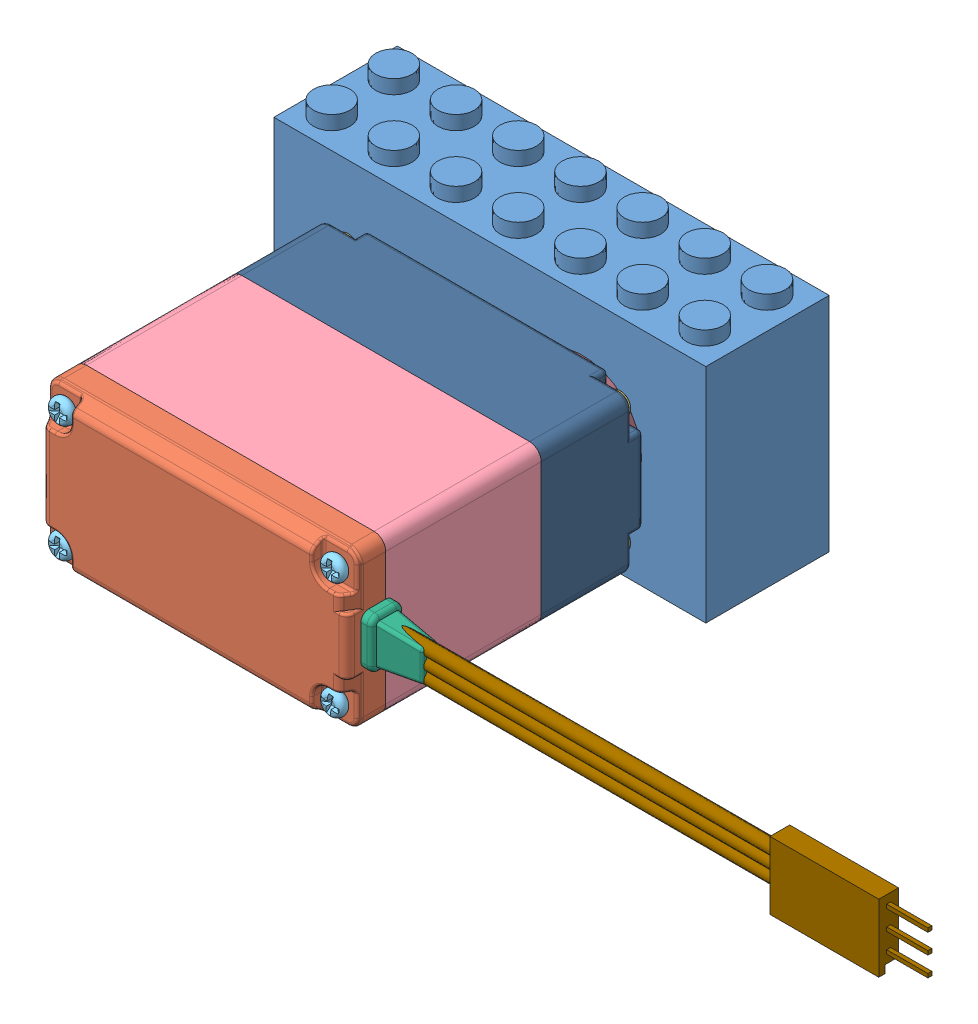
SolidWorks assembly Assembly of motor to mount, configuration Default. Lengths in mm.
Overall size (120.89 30.38 56.59).
22 component instances, 13 part files, 12 mates.
Components (placement in the parent):
- Vex Motor to LEGO mount-1: Vex Motor to LEGO mount [Default] at (39.2754 -37.007 4.4169) size (55.56 30.38 15.87)
- VEX-MOTOR-1: VEX-MOTOR [Default] at (-25.3861 -22.7195 0.5263) size (111.13 20 53.77)
  - Vex-Motor-Bottom-Plate-1: Vex-Motor-Bottom-Plate [Default] at (0 0 25) x (-1 0 0) z (0 0 -1) size (40.01 20 5)
  - Vex-Motor-Screw-Top-Simple-1: Vex-Motor-Screw-Top-Simple [Default] at (17.5 -7.5 -1.6) x (1 0 0) z (0 1 0) size (3.04 1.35 3.04)
  - Vex-Motor-Bottom-Housing-1: Vex-Motor-Bottom-Housing [Default] at origin size (40 20 27)
  - Vex-Motor-Screw-Bottom-Simple-1: Vex-Motor-Screw-Bottom-Simple [Default] at (-17.5 7.5 22.5) x (1 0 0) z (0 -1 0) size (3.04 1.35 3.04)
  - Vex-Wire-Support-1: Vex-Wire-Support [Default] at (18.6 0 21.1) x (0 1 0) z (-1 0 0) size (6.41 4.2 9.6)
  - Vex-Motor-Output-Gear-1: Vex-Motor-Output-Gear [Default] at (9.9 0 -3.25) x (0.000313 1 0) z (0 0 -1) size (17.29 17.28 12.55)
  - Insert-Nut-632-Simple-1: Insert-Nut-632-Simple [Default] at (-2.8 0 -19.4731) x (0.660354 0.750955 0) z (-0.750955 0.660354 0) size (5.5 9.3 5.5)
  - Vex-Motor-Screw-Top-Simple-2: Vex-Motor-Screw-Top-Simple [Default] at (17.5 7.5 -1.6) x (1 0 0) z (0 1 0) size (3.04 1.35 3.04)
  - Vex-Motor-PWM-1: Vex-Motor-PWM [Default] at (78.8 0 21.1) x (-1 0 0) z (0 0 1) size (69.31 8.7 2.54)
  - Vex-Motor-Screw-Bottom-Simple-2: Vex-Motor-Screw-Bottom-Simple [Default] at (17.5 7.5 22.5) x (-1 0 0) z (0 1 0) size (3.04 1.35 3.04)
  - Vex-Motor-Screw-Bottom-Simple-3: Vex-Motor-Screw-Bottom-Simple [Default] at (17.5 -7.5 22.5) x (0.990547 -0.137172 0) z (-0.137172 -0.990547 0) size (3.04 1.35 3.04)
  - Vex-Motor-Screw-Top-Simple-3: Vex-Motor-Screw-Top-Simple [Default] at (-17.5 7.5 -1.6) x (1 0 0) z (0 1 0) size (3.04 1.35 3.04)
  - Vex-Motor-Screw-Bottom-Simple-4: Vex-Motor-Screw-Bottom-Simple [Default] at (-17.5 -7.5 22.5) x (1 0 0) z (0 -1 0) size (3.04 1.35 3.04)
  - Vex-Motor-Top-Housing-1: Vex-Motor-Top-Housing [Default] x (1 0 0) z (0 0 -1) size (40.03 20 28.1)
  - Insert-Nut-632-Simple-2: Insert-Nut-632-Simple [Default] at (-15.5 0 -19.4731) x (-0.689985 0.723823 0) z (-0.723823 -0.689985 0) size (5.5 9.3 5.5)
  - Vex-Motor-Screw-Top-Simple-4: Vex-Motor-Screw-Top-Simple [Default] at (-17.5 -7.5 -1.6) x (1 0 0) z (0 1 0) size (3.04 1.35 3.04)
- SCREW-632-0250-1: SCREW-632-0250 [Default] at (-28.1861 -22.7195 -30.6979) x (0 0 1) z (-0.711116 0.703075 0) size (8.57 6.68 6.65)
- SCREW-632-0250-2: SCREW-632-0250 [Default] at (-40.8861 -22.7195 -30.6979) x (0 0 1) z (-0.674774 0.738024 0) size (8.57 6.68 6.65)
- SHAFT ,4375-2: SHAFT ,4375 [Default] at (-15.4611 -22.6945 5.9638) x (1 -0.000313 0) z (0 0 1) size (4.18 4.18 11.22)
- Vex to LEGO shaft coupler-1: Vex to LEGO shaft coupler [Default] at (-15.4861 -22.7195 -13.0862) x (-0.035379 0.999374 0) z (-0.999374 -0.035379 0) size (14.48 12.95 14.48)
Mates (geometry in assembly coordinates):
- Coincident1: coincident anti-aligned: plane of Vex Motor to LEGO mount-1 through (-27.3923 -71.4587 -27.5737) normal (0 0 1); plane of VEX-MOTOR-1/Vex-Motor-Top-Housing-1 through (-40.8861 -22.7195 -27.5737) normal (0 0 -1)
- Concentric1: concentric anti-aligned: circle of Vex Motor to LEGO mount-1; circle of VEX-MOTOR-1/Vex-Motor-Top-Housing-1
- Parallel1: parallel aligned: plane of Vex Motor to LEGO mount-1 through (-55.1736 -8.432 -46.6237) normal (-1 0 0); plane of VEX-MOTOR-1/Vex-Motor-Top-Housing-1 through (-45.3861 -32.7195 0.5263) normal (-1 0 0)
- Concentric4: concentric aligned: cylinder of VEX-MOTOR-1/Insert-Nut-632-Simple-2 through (-40.8861 -22.7195 -14.6891) axis (0 0 -1) radius 1.8589; cylinder of SCREW-632-0250-2 through (-40.8861 -22.7195 -30.6979) axis (0 0 -1) radius 1.7082
- Coincident3: coincident anti-aligned: plane of Vex Motor to LEGO mount-1 through (-40.8861 -22.7195 -28.8437) normal (0 0 -1); plane of SCREW-632-0250-2 through (-39.6254 -21.5669 -28.8437) normal (0 0 1)
- Concentric5: concentric aligned: cylinder of VEX-MOTOR-1/Insert-Nut-632-Simple-1 through (-28.1861 -22.7195 -14.6891) axis (0 0 -1) radius 1.8589; cylinder of SCREW-632-0250-1 through (-28.1861 -22.7195 -30.6979) axis (0 0 -1) radius 1.7082
- Coincident4: coincident anti-aligned: plane of Vex Motor to LEGO mount-1 through (-40.8861 -22.7195 -28.8437) normal (0 0 -1); plane of SCREW-632-0250-1 through (-26.9851 -21.5048 -28.8437) normal (0 0 1)
- Coincident6: coincident anti-aligned: plane of VEX-MOTOR-1/Vex-Motor-Output-Gear-1 through (-17.0981 -21.1065 -14.1737) normal (-0.000313 -1 0); plane of SHAFT ,4375-2 through (-17.0481 -21.1065 31.3638) normal (0.000313 1 0)
- Coincident7: coincident anti-aligned: plane of VEX-MOTOR-1/Vex-Motor-Output-Gear-1 through (-13.8731 -21.1075 -14.1737) normal (-1 0.000313 0); plane of SHAFT ,4375-2 through (-13.8741 -24.2825 31.3638) normal (1 -0.000313 0)
- Coincident8: coincident anti-aligned: plane of VEX-MOTOR-1/Vex-Motor-Output-Gear-1 through (-15.4861 -22.7195 -8.3237) normal (0 0 -1); plane of SHAFT ,4375-2 through (-26.261 -26.1836 -8.3237) normal (0 0 1)
- Coincident9: coincident anti-aligned: plane of SHAFT ,4375-2 through (-17.0481 -21.1065 -19.4362) normal (0 0 -1); plane of Vex to LEGO shaft coupler-1 through (-14.9176 -38.7766 -19.4362) normal (0 0 1)
- Concentric6: concentric anti-aligned: circle of VEX-MOTOR-1/Vex-Motor-Top-Housing-1; circle of Vex to LEGO shaft coupler-1
